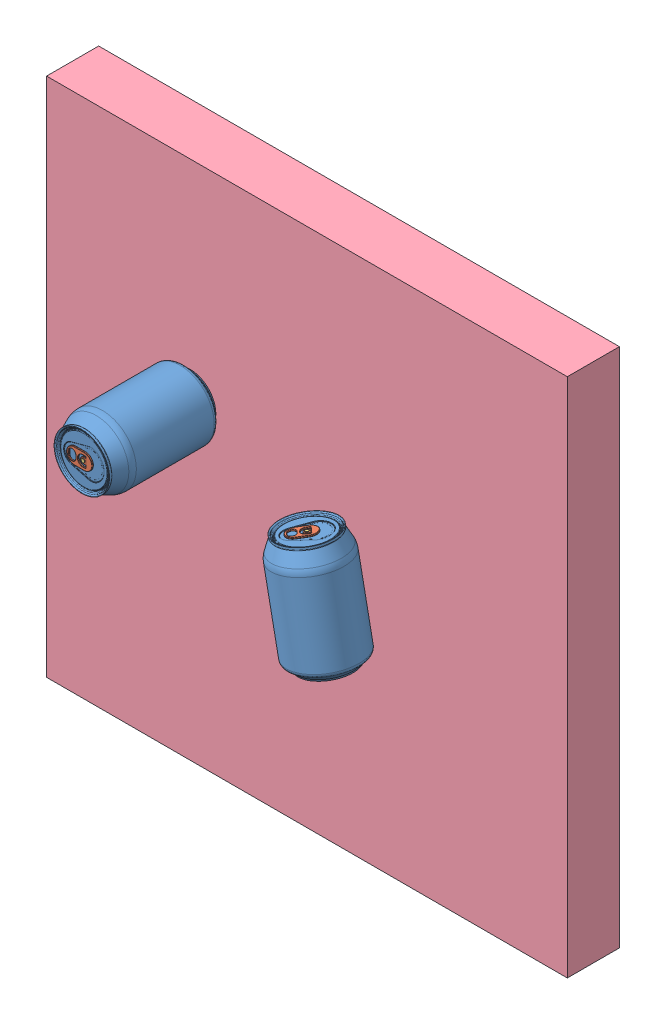
SolidWorks assembly 33cl-CAN, configuration Default. Lengths in mm.
Overall size (508 508 156.8).
10 component instances, 4 part files, 3 mates.
Components (placement in the parent):
- 33cl-CAN.stp-1: 33cl-CAN.stp [Default] at origin size (66 66 106)
  - 33cl-CAN_1.stp-1: 33cl-CAN_1.stp [Default] at (26.7922 30.6101 -52.5247) size (66 66 106)
  - CAN-cap.stp-1: CAN-cap.stp [Default] at (35.7278 22.8601 52.4753) x (-1 0 0) z (0 0 -1) size (25 15.5 1.5)
  - Cap-lock.stp-1: Cap-lock.stp [Default] at (26.7922 30.6101 50.8753) x (0.431999 0.901874 0) z (0 0 1) size (3.5 3.5 2.1)
- table-1: table [Default] at (394.427 -274.9677 -103.3247) size (508 508 50.8)
- can can-1: can can [Default] at (188.5071 -41.3888 20.8456) x (0.652931 0.13001 -0.746176) z (-0.195284 0.980747 0) size (66 66 106)
  - 33cl-CAN.stp-1: 33cl-CAN.stp [Default] at origin size (66 66 106)
    - 33cl-CAN_1.stp-1: 33cl-CAN_1.stp [Default] at (26.7922 30.6101 -52.5247) size (66 66 106)
    - CAN-cap.stp-1: CAN-cap.stp [Default] at (35.7278 22.8601 52.4753) x (-1 0 0) z (0 0 -1) size (25 15.5 1.5)
    - Cap-lock.stp-1: Cap-lock.stp [Default] at (26.7922 30.6101 50.8753) x (0.431999 0.901874 0) z (0 0 1) size (3.5 3.5 2.1)
Mates (geometry in assembly coordinates):
- Coincident1: coincident anti-aligned: plane of 33cl-CAN.stp-1/33cl-CAN_1.stp-1 through (26.7922 30.6101 -52.5247) normal (0 0 -1); plane of table-1 through (394.427 -274.9677 -52.5247) normal (0 0 1)
- Tangent1: tangent anti-aligned: plane of table-1 through (394.427 -274.9677 -52.5247) normal (0 0 1); cylinder of can can-1/33cl-CAN.stp-1/33cl-CAN_1.stp-1 through (193.857 -93.8794 -19.5247) axis (-0.195284 0.980747 0) radius 33
- Tangent2: tangent anti-aligned: plane of table-1 through (394.427 -274.9677 -52.5247) normal (0 0 1); cylinder of can can-1/33cl-CAN.stp-1/33cl-CAN_1.stp-1 through (193.857 -93.8794 -19.5247) axis (-0.195284 0.980747 0) radius 33
